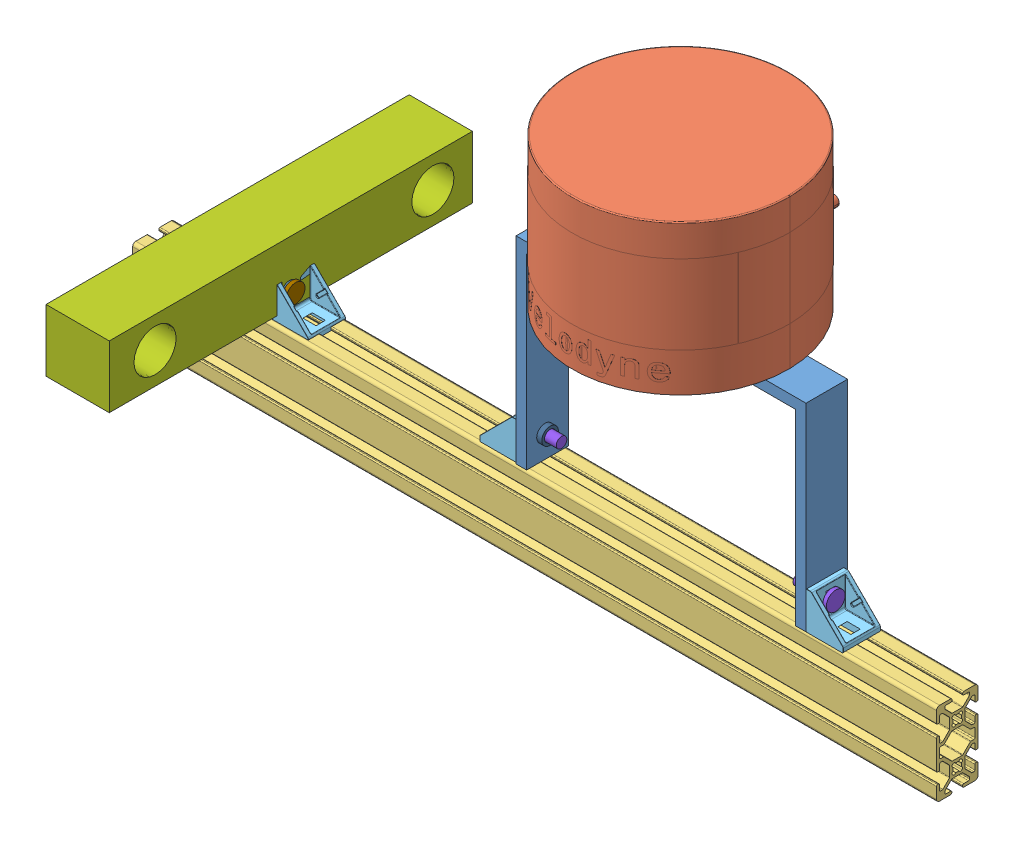
SolidWorks assembly Assem2, configuration Default. Lengths in mm.
Overall size (387.35 207.57 175.01).
15 component instances, 10 part files, 17 mates.
Components (placement in the parent):
- Part3-1: Part3 [Default] at (10.7889 59.902 100.5889) size (139.7 95.43 20.07)
- Copy of Velodyne.catpart^Assem2-1: Copy of Velodyne.catpart^Assem2 [Default] at (50.3184 112.6895 110.72) x (-0.999917 0 0.012901) z (0 1 0) size (104.27 156.21 72.14) (virtual)
- 8020-2040_master-4: 8020-2040_master [Default] at (-3816.4443 21.7838 170.2689) x (0 1 0) z (1 0 0) size (40 20 387.35)
- Screw-1: Screw [Default] at (50.3184 107.4538 110.72) x (0.995268 0 0.097168) z (0 -1 0) size (18 18 13.1)
- 8020 - 14060-2: 8020 - 14060 [Default] at (120.5735 17.1793 111.5889) x (0 0 -1) z (1 0 0) size (18 19.77 19.77)
- 8020 - 14060-3: 8020 - 14060 [Default] at (-19.4774 17.1335 110.6425) x (0 0 1) z (-1 0 0) size (18 19.77 19.77)
- screw2-2: screw2 [Default] at (6.4254 106.1784 110.6219) x (0.929629 0 -0.368498) z (0.368498 0 0.929629) size (13 7.37 13)
- screw2-3: screw2 [Default] at (95.3254 105.7613 110.6219) x (0.978234 0 0.207505) z (-0.207505 0 0.978234) size (13 7.37 13)
- 8020 - 14060-7: 8020 - 14060 [Default] at (-138.9385 15.3972 109.8247) x (0 0 -1) z (1 0 0) size (18 19.77 19.77)
- ZED-5: ZED [Default] at (-166.4185 30.2254 40.0697) x (0 0 -1) z (1 0 0) size (175.01 29.97 30.48)
- screw3-2: screw3 [Default] at (126.2198 20.4854 101.999) x (0 -0.974858 -0.222827) z (-1 0 0) size (9 9 18.03)
- screw3-4: screw3 [Default] at (-23.951 15.8721 111.5379) x (0 -0.779945 -0.625848) z (1 0 0) size (9 9 18.03)
- screw4-1: screw4 [Default] at (-132.9861 20.0555 122.923) x (0 0 1) z (-1 0 0) size (9 9 6.86)
- Nut-1: Nut [Default] at (-13.9738 28.5667 111.7923) x (0 0.326312 -0.945262) z (1 0 0) size (8 8 2.54)
- Nut-3: Nut [Default] at (112.499 28.5667 111.7923) x (0 -0.014153 -0.9999) z (1 0 0) size (8 8 2.54)
Mates (geometry in assembly coordinates):
- Coincident3: coincident anti-aligned: plane of Part3-1 through (120.7254 112.6895 120.6549) normal (0 1 0); plane of Copy of Velodyne.catpart^Assem2-1 through (50.3184 112.6895 110.72) normal (0 -1 0)
- Coincident9: coincident anti-aligned: plane of Part3-1 through (115.6454 17.2595 120.6549) normal (0 -1 0); plane of 8020-2040_master-4 through (-203.7943 17.2595 102.0889) normal (0 1 0)
- Coincident10: coincident aligned: plane of Part3-1 through (10.7889 59.902 100.5889) normal (0 0 -1); plane of 8020-2040_master-4 through (-203.7943 10.3975 100.5889) normal (0 0 -1)
- Parallel9: parallel: plane of 8020-2040_master-4 through (-203.7943 17.2595 113.7269) normal (0 1 0); line of 8020 - 14060-2 through (138.5735 19.2712 120.4889) axis (0 0 -1)
- Parallel10: parallel: plane of 8020-2040_master-4 through (-203.7943 17.2595 102.0889) normal (0 1 0); line of 8020 - 14060-3 through (-37.4774 19.2254 101.7425) axis (0 0 1)
- Concentric13: concentric anti-aligned: circle of Copy of Velodyne.catpart^Assem2-1; cylinder of Screw-1 through (50.3184 116.4867 110.72) axis (0 -1 0) radius 7.11
- Tangent13: tangent aligned: cylinder of 8020-2040_master-4 through (-203.7943 15.7595 119.0889) axis (1 0 0) radius 1.5; plane of 8020 - 14060-2 through (122.6654 34.1793 120.5889) normal (0 0 1)
- Concentric16: concentric anti-aligned: circle of Part3-1; cylinder of screw2-2 through (6.4254 113.5444 110.6219) axis (0 -1 0) radius 5.5
- Concentric17: concentric aligned: circle of Part3-1; circle of screw2-3
- Parallel14: parallel aligned: plane of 8020-2040_master-4 through (-203.7943 17.2595 102.0889) normal (0 1 0); plane of 8020 - 14060-7 through (-134.9385 18.3972 102.8247) normal (0 1 0)
- Coincident35: coincident aligned: plane of 8020 - 14060-7 through (-135.9385 32.9033 102.8247) normal (1 0 0); plane of ZED-5 through (-135.9385 30.2254 40.0697) normal (1 0 0)
- Parallel17: parallel aligned: plane of 8020-2040_master-4 through (-203.7943 17.2595 102.0889) normal (0 1 0); plane of 8020 - 14060-2 through (124.5735 20.1793 104.5889) normal (0 1 0)
- Concentric22: concentric anti-aligned: cylinder of Part3-1 through (162.6354 28.5667 111.7923) axis (-1 0 0) radius 3.2932; cylinder of screw3-2 through (108.1858 28.5667 111.7923) axis (1 0 0) radius 2.55
- Concentric23: concentric aligned: cylinder of Part3-1 through (162.6354 28.5667 111.7923) axis (-1 0 0) radius 3.2932; cylinder of screw3-4 through (-5.917 28.5667 111.7923) axis (-1 0 0) radius 2.55
- Concentric26: concentric anti-aligned: circle of ZED-5; circle of screw4-1
- Concentric27: concentric aligned: circle of screw3-4; circle of Nut-1
- Concentric28: concentric anti-aligned: circle of screw3-2; circle of Nut-3
